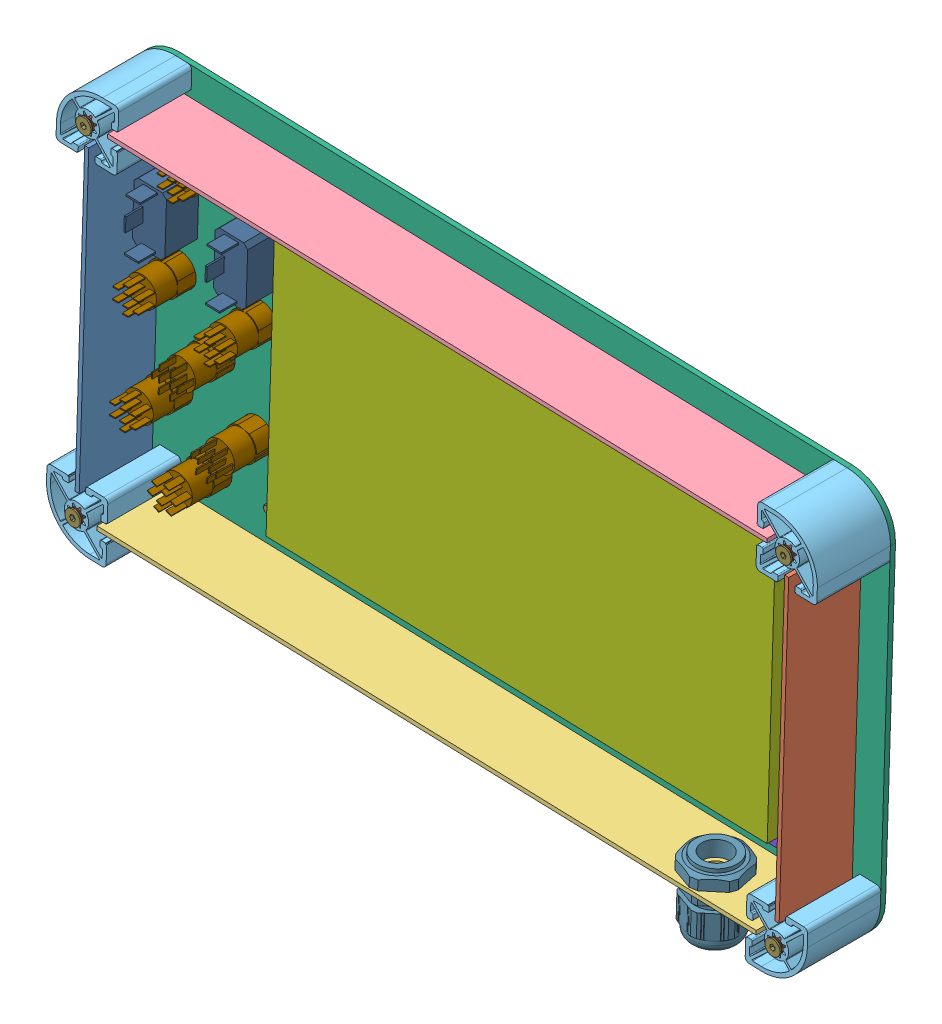
SolidWorks assembly BTEC 2019 - Montagem teclado, configuration Valor predeterminado. Lengths in mm.
Overall size (381.11 222.57 65).
42 component instances, 15 part files, 97 mates.
Components (placement in the parent):
- BTEC 2019 - Teclado base-1: BTEC 2019 - Teclado base [Default] at (-6.1201 -200.4879 117.0502) x (0.999504 -0.031491 0) z (0 0 1) size (375 200 2) (hidden)
- BTEC 2019 - Teclado lateral direita-1: BTEC 2019 - Teclado lateral direita [Valor predeterminado] at (-177.535 -195.0872 99.0502) x (-0.031491 -0.999504 0) z (0 0 1) size (150 2 36)
- BTEC 2019 - Teclado lateral esquerda-1: BTEC 2019 - Teclado lateral esquerda [Valor predeterminado] at (167.2938 -205.9515 99.0502) x (0.031491 0.999504 0) z (0 0 -1) size (150 2 36)
- BTEC 2019 - Teclado lateral inferior-1: BTEC 2019 - Teclado lateral inferior [Valor predeterminado] at (-8.7653 -284.4462 99.0502) x (0.999504 -0.031491 0) z (0 0 1) size (325 2 36)
- BTEC 2019 - Teclado lateral superior-1: BTEC 2019 - Teclado lateral superior [Valor predeterminado] at (-3.4749 -116.5295 99.0502) x (0.999504 -0.031491 0) z (0 0 -1) size (325 2 36)
- Perfil Famak 01 007 0027-1: Perfil Famak 01 007 0027 [Valor predeterminado] at (163.6176 -290.8779 181.0502) x (0 0 -1) z (0.031491 0.999504 0) size (36 30 30)
- Perfil Famak 01 007 0027-2: Perfil Famak 01 007 0027 [Valor predeterminado] at (168.9711 -120.9622 181.0502) x (0 0 -1) z (-0.999504 0.031491 0) size (36 30 30)
- Perfil Famak 01 007 0027-3: Perfil Famak 01 007 0027 [Valor predeterminado] at (-181.2113 -280.0135 181.0502) x (0 0 -1) z (0.999504 -0.031491 0) size (36 30 30)
- Perfil Famak 01 007 0027-4: Perfil Famak 01 007 0027 [Valor predeterminado] at (-175.8578 -110.0978 181.0502) x (0 0 -1) z (-0.031491 -0.999504 0) size (36 30 30)
- BTEC 2019 - Teclado moldura-1: BTEC 2019 - Teclado moldura [Default] at (-6.1201 -200.4879 79.8002) x (0.999504 -0.031491 0) z (0 0 -1) size (375 200 2.5)
- Placa eletronica-1: Placa eletronica [Valor predeterminado] at (72.0302 -209.9598 82.5502) x (0.999504 -0.031491 0) z (0 0 1) size (247 130 23)
- BTEC 2019 - Display 2-2: BTEC 2019 - Display 2 [Valor predeterminado] at (168.906 -315.4182 82.5502) x (-0.999504 0.031491 0) z (0 0 -1) size (279.5 158 1.5)
- BCV3 112 102 - Controle botão-1: BCV3 112 102 - Controle botão [Valor predeterminado] at (-126.2454 -186.6982 78.5502) x (1 0 0) z (0 1 0) size (17.7 39.7 17.7)
- BCV3 112 102 - Controle botão-2: BCV3 112 102 - Controle botão [Valor predeterminado] at (-127.82 -236.6734 78.5502) x (0.18993 0.981798 0) z (-0.981798 0.18993 0) size (17.7 39.7 17.7)
- BCV3 112 102 - Controle botão-3: BCV3 112 102 - Controle botão [Valor predeterminado] at (-148.5973 -261.0312 78.5502) x (0.921441 -0.388519 0) z (0.388519 0.921441 0) size (17.7 39.7 17.7)
- BCV3 112 102 - Controle botão-4: BCV3 112 102 - Controle botão [Valor predeterminado] at (-147.0228 -211.056 78.5502) x (0.025682 0.99967 0) z (-0.99967 0.025682 0) size (17.7 39.7 17.7)
- BCV3 112 102 - Controle botão-5: BCV3 112 102 - Controle botão [Valor predeterminado] at (-167.8001 -235.4137 78.5502) x (1 0 0) z (0 1 0) size (17.7 39.7 17.7)
- BCV3 112 102 - Controle botão-6: BCV3 112 102 - Controle botão [Valor predeterminado] at (-166.2256 -185.4385 78.5502) x (-0.999689 0.024955 0) z (-0.024955 -0.999689 0) size (17.7 39.7 17.7)
- BCV3 112 103 - Controle chave geral-1: BCV3 112 103 - Controle chave geral [Default] at (-165.2809 -155.4534 89.0502) x (-0.999504 0.031491 0) z (0 0 -1) size (17 29 51.5)
- BCV3 112 103 - Controle chave geral-2: BCV3 112 103 - Controle chave geral [Default] at (-125.3007 -156.713 89.0502) x (-0.999504 0.031491 0) z (0 0 -1) size (17 29 51.5)
- BCV3 112 102 - Controle botão-7: BCV3 112 102 - Controle botão [Valor predeterminado] at (-144.3461 -126.0981 78.5502) x (1 0 0) z (0 1 0) size (17.7 39.7 17.7)
- BTEC 2019 - Bucha M4-1: BTEC 2019 - Bucha M4 [Valor predeterminado] at (168.9711 -120.9622 99.0502) x (1 0 0) z (0 -1 0) size (6.5 36 6.5)
- BTEC 2019 - Bucha M4-2: BTEC 2019 - Bucha M4 [Valor predeterminado] at (163.6176 -290.8779 99.0502) x (1 0 0) z (0 -1 0) size (6.5 36 6.5)
- BTEC 2019 - Bucha M4-3: BTEC 2019 - Bucha M4 [Valor predeterminado] at (-175.8578 -110.0978 99.0502) x (1 0 0) z (0 -1 0) size (6.5 36 6.5)
- BTEC 2019 - Bucha M4-4: BTEC 2019 - Bucha M4 [Valor predeterminado] at (-181.2113 -280.0135 99.0502) x (-0.180459 -0.983583 0) z (-0.983583 0.180459 0) size (6.5 36 6.5)
- socket countersunk head screw_iso-2: socket countersunk head screw_iso [ISO 10642 - M4 x 12 --- 12N] at (163.6176 -290.8779 78.5502) x (0 0 1) z (-0.759789 -0.650169 0) size (12 7.53 7.53)
- socket countersunk head screw_iso-3: socket countersunk head screw_iso [ISO 10642 - M4 x 12 --- 12N] at (163.6176 -290.8779 119.0502) x (0 0 -1) z (0.525931 -0.850527 0) size (12 7.53 7.53)
- socket countersunk head screw_iso-4: socket countersunk head screw_iso [ISO 10642 - M4 x 12 --- 12N] at (-181.2113 -280.0135 78.5502) x (0 0 1) z (-1 0 0) size (12 7.53 7.53)
- socket countersunk head screw_iso-5: socket countersunk head screw_iso [ISO 10642 - M4 x 12 --- 12N] at (-175.8578 -110.0978 78.5502) x (0 0 1) z (0.031778 0.999495 0) size (12 7.53 7.53)
- socket countersunk head screw_iso-6: socket countersunk head screw_iso [ISO 10642 - M4 x 12 --- 12N] at (168.9711 -120.9622 78.5502) x (0 0 1) z (-1 0 0) size (12 7.53 7.53)
- socket countersunk head screw_iso-7: socket countersunk head screw_iso [ISO 10642 - M4 x 12 --- 12N] at (-181.2113 -280.0135 119.0502) x (0 0 -1) z (0.838265 0.545264 0) size (12 7.53 7.53)
- socket countersunk head screw_iso-8: socket countersunk head screw_iso [ISO 10642 - M4 x 12 --- 12N] at (-175.8578 -110.0978 119.0502) x (0 0 -1) z (0.635819 -0.771838 0) size (12 7.53 7.53)
- socket countersunk head screw_iso-9: socket countersunk head screw_iso [ISO 10642 - M4 x 12 --- 12N] at (168.9711 -120.9622 119.0502) x (0 0 -1) z (-0.751426 -0.659818 0) size (12 7.53 7.53)
- socket countersunk head screw_iso-10: socket countersunk head screw_iso [ISO 10642 - M4 x 12 --- 12N] at (156.9086 -265.6539 78.5502) x (0 0 1) z (-0.921096 -0.389335 0) size (12 7.53 7.53)
- socket countersunk head screw_iso-11: socket countersunk head screw_iso [ISO 10642 - M4 x 12 --- 12N] at (160.6875 -145.7134 78.5502) x (0 0 1) z (-0.921447 -0.388505 0) size (12 7.53 7.53)
- socket countersunk head screw_iso-12: socket countersunk head screw_iso [ISO 10642 - M4 x 12 --- 12N] at (-113.957 -257.1201 78.5502) x (0 0 1) z (-1 0 0) size (12 7.53 7.53)
- socket countersunk head screw_iso-13: socket countersunk head screw_iso [ISO 10642 - M4 x 12 --- 12N] at (-110.1781 -137.1796 78.5502) x (0 0 1) z (-1 0 0) size (12 7.53 7.53)
- hex nut style 1 gradeab_iso-1: hex nut style 1 gradeab_iso [Hexagon Nut ISO - 4032 - M4 - D - N] at (156.9086 -265.6539 85.7502) x (0.537158 -0.843482 0) z (0 0 1) size (7 8.08 3.2)
- hex nut style 1 gradeab_iso-2: hex nut style 1 gradeab_iso [Hexagon Nut ISO - 4032 - M4 - D - N] at (160.6875 -145.7134 85.7502) x (0.928496 0.371343 0) z (0 0 1) size (7 8.08 3.2)
- hex nut style 1 gradeab_iso-3: hex nut style 1 gradeab_iso [Hexagon Nut ISO - 4032 - M4 - D - N] at (-113.957 -257.1201 82.5502) x (0.678434 -0.734661 0) z (0 0 -1) size (7 8.08 3.2)
- hex nut style 1 gradeab_iso-4: hex nut style 1 gradeab_iso [Hexagon Nut ISO - 4032 - M4 - D - N] at (-110.1781 -137.1796 85.7502) size (7 8.08 3.2)
- PRENSA CABO STECK PG 13,5 S802 LI-2: PRENSA CABO STECK PG 13,5 S802 LI [Valor predeterminado] at (118.3502 -298.6562 102.0502) x (-0.031491 -0.999504 0) z (-0.315456 0.009939 0.948888) size (36 28.2 26.2)
Mates (geometry in assembly coordinates):
- Concêntrico46: concentric aligned: circle of BTEC 2019 - Teclado base-1; circle of Perfil Famak 01 007 0027-3
- Concêntrico47: concentric aligned: circle of BTEC 2019 - Teclado base-1; circle of Perfil Famak 01 007 0027-1
- Concêntrico48: concentric aligned: circle of BTEC 2019 - Teclado base-1; circle of Perfil Famak 01 007 0027-2
- Concêntrico49: concentric aligned: circle of BTEC 2019 - Teclado base-1; circle of Perfil Famak 01 007 0027-4
- Coincidente29: coincident anti-aligned: plane of BTEC 2019 - Teclado base-1 through (156.8415 -283.6609 117.0502) normal (0 0 -1); plane of Perfil Famak 01 007 0027-2 through (7.7937 -130.8915 117.0502) normal (0 0 1)
- Coincidente31: coincident anti-aligned: plane of BTEC 2019 - Teclado base-1 through (156.8415 -283.6609 117.0502) normal (0 0 -1); plane of Perfil Famak 01 007 0027-1 through (153.6883 -129.7005 117.0502) normal (0 0 1)
- Coincidente32: coincident anti-aligned: plane of BTEC 2019 - Teclado base-1 through (156.8415 -283.6609 117.0502) normal (0 0 -1); plane of Perfil Famak 01 007 0027-3 through (-20.0339 -270.0842 117.0502) normal (0 0 1)
- Coincidente33: coincident anti-aligned: plane of BTEC 2019 - Teclado base-1 through (156.8415 -283.6609 117.0502) normal (0 0 -1); plane of Perfil Famak 01 007 0027-4 through (-165.9285 -271.2752 117.0502) normal (0 0 1)
- Paralelo1: parallel anti-aligned: plane of BTEC 2019 - Teclado base-1 through (-174.6871 -295.2265 119.0502) normal (-0.031491 -0.999504 0); plane of Perfil Famak 01 007 0027-1 through (159.4923 -275.7404 81.0502) normal (0.031491 0.999504 0)
- Paralelo2: parallel anti-aligned: plane of BTEC 2019 - Teclado base-1 through (183.7432 -128.4311 119.0502) normal (0.999504 -0.031491 0); plane of Perfil Famak 01 007 0027-2 through (153.8336 -125.0875 81.0502) normal (-0.999504 0.031491 0)
- Paralelo3: parallel anti-aligned: plane of BTEC 2019 - Teclado base-1 through (-174.6871 -295.2265 119.0502) normal (-0.031491 -0.999504 0); plane of Perfil Famak 01 007 0027-3 through (-185.3366 -264.8761 81.0502) normal (0.031491 0.999504 0)
- Paralelo4: parallel anti-aligned: plane of BTEC 2019 - Teclado base-1 through (-168.3889 -95.3257 119.0502) normal (0.031491 0.999504 0); plane of Perfil Famak 01 007 0027-4 through (-171.7325 -125.2353 81.0502) normal (-0.031491 -0.999504 0)
- Coincidente42: coincident anti-aligned: plane of BTEC 2019 - Teclado base-1 through (156.8415 -283.6609 117.0502) normal (0 0 -1); plane of BTEC 2019 - Teclado lateral direita-1 through (-181.8959 -269.987 117.0502) normal (0 0 1)
- Distância1: distance = 5 mm anti-aligned: plane of BTEC 2019 - Teclado lateral direita-1 through (-177.1722 -120.0614 81.0502) normal (0.031491 0.999504 0); plane of Perfil Famak 01 007 0027-4 through (-189.3237 -124.681 81.0502) normal (-0.031491 -0.999504 0)
- Distância2: distance = 3.1 mm anti-aligned: plane of Perfil Famak 01 007 0027-4 through (-180.4124 -124.4615 81.0502) normal (0.999504 -0.031491 0); plane of BTEC 2019 - Teclado lateral direita-1 through (-181.8959 -269.987 117.0502) normal (-0.999504 0.031491 0)
- Coincidente46: coincident anti-aligned: plane of BTEC 2019 - Teclado base-1 through (156.8415 -283.6609 117.0502) normal (0 0 -1); plane of BTEC 2019 - Teclado lateral esquerda-1 through (169.6557 -130.9887 117.0502) normal (0 0 1)
- Distância4: distance = 5 mm anti-aligned: plane of BTEC 2019 - Teclado lateral esquerda-1 through (167.6567 -130.9257 117.0502) normal (0.031491 0.999504 0); plane of Perfil Famak 01 007 0027-2 through (173.0964 -136.0996 81.0502) normal (-0.031491 -0.999504 0)
- Coincidente49: coincident anti-aligned: plane of BTEC 2019 - Teclado base-1 through (156.8415 -283.6609 117.0502) normal (0 0 -1); plane of BTEC 2019 - Teclado lateral superior-1 through (158.9445 -121.6468 117.0502) normal (0 0 1)
- Distância5: distance = 5 mm anti-aligned: plane of BTEC 2019 - Teclado lateral superior-1 through (-165.8313 -109.4133 117.0502) normal (-0.999504 0.031491 0); plane of Perfil Famak 01 007 0027-4 through (-161.2747 -123.5638 81.0502) normal (0.999504 -0.031491 0)
- Distância6: distance = 3.1 mm anti-aligned: plane of BTEC 2019 - Teclado lateral superior-1 through (159.0075 -119.6478 81.0502) normal (0.031491 0.999504 0); plane of Perfil Famak 01 007 0027-4 through (-163.3863 -106.3887 81.0502) normal (-0.031491 -0.999504 0)
- Coincidente52: coincident anti-aligned: plane of BTEC 2019 - Teclado base-1 through (156.8415 -283.6609 117.0502) normal (0 0 -1); plane of BTEC 2019 - Teclado lateral inferior-1 through (153.5911 -291.5625 117.0502) normal (0 0 1)
- Coincidente72: coincident anti-aligned: plane of Perfil Famak 01 007 0027-1 through (151.0335 -277.4749 81.0502) normal (0 0 -1); plane of BTEC 2019 - Teclado moldura-1 through (161.7541 -127.7383 81.0502) normal (0 0 1)
- Distância11: distance = 3.1 mm anti-aligned: plane of Perfil Famak 01 007 0027-1 through (168.1722 -276.5142 81.0502) normal (-0.999504 0.031491 0); plane of BTEC 2019 - Teclado lateral esquerda-1 through (169.6557 -130.9887 81.0502) normal (0.999504 -0.031491 0)
- Distância21: distance = 16 mm anti-aligned: plane of Placa eletronica-1 through (147.5393 -261.3569 105.5502) normal (0.999504 -0.031491 0); plane of BTEC 2019 - Teclado lateral esquerda-1 through (167.6567 -130.9257 81.0502) normal (-0.999504 0.031491 0)
- Concêntrico54: concentric anti-aligned: circle of Perfil Famak 01 007 0027-4; circle of BTEC 2019 - Teclado moldura-1
- Concêntrico55: concentric anti-aligned: circle of Perfil Famak 01 007 0027-2; circle of BTEC 2019 - Teclado moldura-1
- Concêntrico56: concentric anti-aligned: circle of Perfil Famak 01 007 0027-1; circle of BTEC 2019 - Teclado moldura-1
- Concêntrico57: concentric anti-aligned: circle of Perfil Famak 01 007 0027-3; circle of BTEC 2019 - Teclado moldura-1
- Coincidente91: coincident anti-aligned: plane of BTEC 2019 - Teclado moldura-1 through (161.7541 -127.7383 81.0502) normal (0 0 1); plane of BTEC 2019 - Display 2-2 through (168.906 -315.4182 81.0502) normal (0 0 -1)
- Distância23: distance = 1.5 mm anti-aligned: plane of BTEC 2019 - Display 2-2 through (165.9684 -136.8755 72.5502) normal (0.999504 -0.031491 0); plane of BTEC 2019 - Teclado lateral esquerda-1 through (167.6567 -130.9257 81.0502) normal (-0.999504 0.031491 0)
- Distância24: distance = 5 mm aligned: plane of Placa eletronica-1 through (-95.2444 -123.6431 105.5502) normal (0.031491 0.999504 0); plane of BTEC 2019 - Display 2-2 through (174.8377 -127.15 81.0502) normal (0.031491 0.999504 0)
- Concêntrico58: concentric aligned: cylinder of BTEC 2019 - Teclado moldura-1 through (-126.2454 -186.6982 88.5502) axis (0 0 -1) radius 8; cylinder of BCV3 112 102 - Controle botão-1 through (-126.2454 -186.6982 99.8502) axis (0 0 -1) radius 7.25
- Coincidente92: coincident anti-aligned: plane of BTEC 2019 - Teclado moldura-1 through (161.7541 -127.7383 78.5502) normal (0 0 -1); plane of BCV3 112 102 - Controle botão-1 through (-126.2454 -186.6982 78.5502) normal (0 0 1)
- Concêntrico59: concentric anti-aligned: cylinder of BTEC 2019 - Teclado moldura-1 through (-166.2256 -185.4385 88.5502) axis (0 0 -1) radius 8; cylinder of BCV3 112 102 - Controle botão-6 through (-166.2256 -185.4385 72.1502) axis (0 0 1) radius 8.85
- Coincidente93: coincident anti-aligned: plane of BTEC 2019 - Teclado moldura-1 through (161.7541 -127.7383 78.5502) normal (0 0 -1); plane of BCV3 112 102 - Controle botão-6 through (-166.2256 -185.4385 78.5502) normal (0 0 1)
- Concêntrico60: concentric anti-aligned: circle of BTEC 2019 - Teclado moldura-1; cylinder of BCV3 112 102 - Controle botão-4 through (-147.0228 -211.056 99.8502) axis (0 0 -1) radius 7.25
- Coincidente95: coincident anti-aligned: plane of BTEC 2019 - Teclado moldura-1 through (161.7541 -127.7383 78.5502) normal (0 0 -1); plane of BCV3 112 102 - Controle botão-4 through (-147.0228 -211.056 78.5502) normal (0 0 1)
- Coincidente96: coincident anti-aligned: plane of BTEC 2019 - Teclado moldura-1 through (161.7541 -127.7383 78.5502) normal (0 0 -1); plane of BCV3 112 102 - Controle botão-2 through (-127.82 -236.6734 78.5502) normal (0 0 1)
- Coincidente97: coincident anti-aligned: plane of BTEC 2019 - Teclado moldura-1 through (161.7541 -127.7383 78.5502) normal (0 0 -1); plane of BCV3 112 102 - Controle botão-3 through (-148.5973 -261.0312 78.5502) normal (0 0 1)
- Coincidente98: coincident anti-aligned: plane of BTEC 2019 - Teclado moldura-1 through (161.7541 -127.7383 78.5502) normal (0 0 -1); plane of BCV3 112 102 - Controle botão-5 through (-167.8001 -235.4137 78.5502) normal (0 0 1)
- Concêntrico61: concentric aligned: cylinder of BTEC 2019 - Teclado moldura-1 through (-167.8001 -235.4137 88.5502) axis (0 0 -1) radius 8; cylinder of BCV3 112 102 - Controle botão-5 through (-167.8001 -235.4137 99.8502) axis (0 0 -1) radius 7.25
- Concêntrico62: concentric anti-aligned: circle of BTEC 2019 - Teclado moldura-1; cylinder of BCV3 112 102 - Controle botão-3 through (-148.5973 -261.0312 99.8502) axis (0 0 -1) radius 7.25
- Concêntrico63: concentric aligned: cylinder of BTEC 2019 - Teclado moldura-1 through (-127.82 -236.6734 88.5502) axis (0 0 -1) radius 8; cylinder of BCV3 112 102 - Controle botão-2 through (-127.82 -236.6734 99.8502) axis (0 0 -1) radius 7.25
- Concêntrico65: concentric anti-aligned: cylinder of BTEC 2019 - Teclado moldura-1 through (-165.2809 -155.4534 88.5502) axis (0 0 -1) radius 6; cylinder of BCV3 112 103 - Controle chave geral-1 through (-165.2809 -155.4534 68.0502) axis (0 0 1) radius 5.85
- Coincidente100: coincident anti-aligned: plane of BTEC 2019 - Teclado moldura-1 through (161.7541 -127.7383 81.0502) normal (0 0 1); plane of BCV3 112 103 - Controle chave geral-1 through (-157.7415 -170.1982 81.0502) normal (0 0 -1)
- Paralelo5: parallel aligned: plane of BTEC 2019 - Teclado moldura-1 through (-195.9834 -272.5446 78.5502) normal (-0.999504 0.031491 0); plane of BCV3 112 103 - Controle chave geral-1 through (-172.8203 -140.7087 81.0502) normal (-0.999504 0.031491 0)
- Concêntrico66: concentric anti-aligned: cylinder of BTEC 2019 - Teclado moldura-1 through (-125.3007 -156.713 88.5502) axis (0 0 -1) radius 6; cylinder of BCV3 112 103 - Controle chave geral-2 through (-125.3007 -156.713 68.0502) axis (0 0 1) radius 5.85
- Coincidente102: coincident anti-aligned: plane of BTEC 2019 - Teclado moldura-1 through (161.7541 -127.7383 81.0502) normal (0 0 1); plane of BCV3 112 103 - Controle chave geral-2 through (-117.7613 -171.4578 81.0502) normal (0 0 -1)
- Paralelo6: parallel aligned: plane of BTEC 2019 - Teclado lateral direita-1 through (-181.8959 -269.987 117.0502) normal (-0.999504 0.031491 0); plane of BCV3 112 103 - Controle chave geral-2 through (-132.8401 -141.9683 81.0502) normal (-0.999504 0.031491 0)
- Concêntrico67: concentric aligned: cylinder of BTEC 2019 - Teclado moldura-1 through (-144.3461 -126.0981 88.5502) axis (0 0 -1) radius 8; cylinder of BCV3 112 102 - Controle botão-7 through (-144.3461 -126.0981 99.8502) axis (0 0 -1) radius 7.25
- Coincidente104: coincident anti-aligned: plane of BTEC 2019 - Teclado moldura-1 through (161.7541 -127.7383 78.5502) normal (0 0 -1); plane of BCV3 112 102 - Controle botão-7 through (-144.3461 -126.0981 78.5502) normal (0 0 1)
- Coincidente105: coincident anti-aligned: plane of Placa eletronica-1 through (72.0302 -209.9598 82.5502) normal (0 0 -1); plane of BTEC 2019 - Display 2-2 through (168.906 -315.4182 82.5502) normal (0 0 1)
- Distância25: distance = 1 mm anti-aligned: plane of Perfil Famak 01 007 0027-2 through (155.5051 -135.5454 81.0502) normal (-0.031491 -0.999504 0); plane of BTEC 2019 - Display 2-2 through (174.5228 -137.145 81.0502) normal (0.031491 0.999504 0)
- Concêntrico68: concentric anti-aligned: cylinder of Perfil Famak 01 007 0027-4 through (-175.8578 -110.0978 81.0502) axis (0 0 1) radius 3.25; cylinder of BTEC 2019 - Bucha M4-3 through (-175.8578 -110.0978 117.0502) axis (0 0 -1) radius 3.25
- Coincidente106: coincident anti-aligned: plane of BTEC 2019 - Teclado moldura-1 through (161.7541 -127.7383 81.0502) normal (0 0 1); plane of BTEC 2019 - Bucha M4-3 through (-175.8578 -110.0978 81.0502) normal (0 0 -1)
- Concêntrico69: concentric anti-aligned: cylinder of Perfil Famak 01 007 0027-3 through (-181.2113 -280.0135 81.0502) axis (0 0 1) radius 3.25; cylinder of BTEC 2019 - Bucha M4-4 through (-181.2113 -280.0135 117.0502) axis (0 0 -1) radius 3.25
- Coincidente107: coincident anti-aligned: plane of BTEC 2019 - Teclado moldura-1 through (161.7541 -127.7383 81.0502) normal (0 0 1); plane of BTEC 2019 - Bucha M4-4 through (-181.2113 -280.0135 81.0502) normal (0 0 -1)
- Concêntrico70: concentric anti-aligned: cylinder of Perfil Famak 01 007 0027-2 through (168.9711 -120.9622 81.0502) axis (0 0 1) radius 3.25; cylinder of BTEC 2019 - Bucha M4-1 through (168.9711 -120.9622 117.0502) axis (0 0 -1) radius 3.25
- Coincidente108: coincident anti-aligned: plane of BTEC 2019 - Teclado moldura-1 through (161.7541 -127.7383 81.0502) normal (0 0 1); plane of BTEC 2019 - Bucha M4-1 through (168.9711 -120.9622 81.0502) normal (0 0 -1)
- Concêntrico71: concentric anti-aligned: cylinder of Perfil Famak 01 007 0027-1 through (163.6176 -290.8779 81.0502) axis (0 0 1) radius 3.25; cylinder of BTEC 2019 - Bucha M4-2 through (163.6176 -290.8779 117.0502) axis (0 0 -1) radius 3.25
- Coincidente110: coincident anti-aligned: plane of BTEC 2019 - Teclado moldura-1 through (161.7541 -127.7383 81.0502) normal (0 0 1); plane of BTEC 2019 - Bucha M4-2 through (163.6176 -290.8779 81.0502) normal (0 0 -1)
- Concêntrico72: concentric anti-aligned: cylinder of BTEC 2019 - Bucha M4-2 through (163.6176 -290.8779 117.0502) axis (0 0 1) radius 1.65; cylinder of socket countersunk head screw_iso-2 through (163.6176 -290.8779 78.5502) axis (0 0 -1) radius 2
- Coincidente111: coincident aligned: plane of BTEC 2019 - Teclado moldura-1 through (161.7541 -127.7383 78.5502) normal (0 0 -1); plane of socket countersunk head screw_iso-2 through (163.6176 -290.8779 78.5502) normal (0 0 -1)
- Concêntrico73: concentric aligned: cylinder of BTEC 2019 - Bucha M4-2 through (163.6176 -290.8779 117.0502) axis (0 0 1) radius 1.65; cylinder of socket countersunk head screw_iso-3 through (163.6176 -290.8779 119.0502) axis (0 0 1) radius 2
- Coincidente112: coincident aligned: plane of BTEC 2019 - Teclado base-1 through (156.8415 -283.6609 119.0502) normal (0 0 1); plane of socket countersunk head screw_iso-3 through (163.6176 -290.8779 119.0502) normal (0 0 1)
- Concêntrico74: concentric anti-aligned: cylinder of BTEC 2019 - Bucha M4-3 through (-175.8578 -110.0978 117.0502) axis (0 0 1) radius 1.65; cylinder of socket countersunk head screw_iso-5 through (-175.8578 -110.0978 78.5502) axis (0 0 -1) radius 2
- Coincidente113: coincident aligned: plane of BTEC 2019 - Teclado moldura-1 through (161.7541 -127.7383 78.5502) normal (0 0 -1); plane of socket countersunk head screw_iso-5 through (-175.8578 -110.0978 78.5502) normal (0 0 -1)
- Concêntrico75: concentric anti-aligned: cylinder of BTEC 2019 - Bucha M4-4 through (-181.2113 -280.0135 117.0502) axis (0 0 1) radius 1.65; cylinder of socket countersunk head screw_iso-4 through (-181.2113 -280.0135 78.5502) axis (0 0 -1) radius 2
- Coincidente114: coincident aligned: plane of BTEC 2019 - Teclado moldura-1 through (161.7541 -127.7383 78.5502) normal (0 0 -1); circle of socket countersunk head screw_iso-4
- Concêntrico76: concentric anti-aligned: cylinder of BTEC 2019 - Bucha M4-1 through (168.9711 -120.9622 117.0502) axis (0 0 1) radius 1.65; cylinder of socket countersunk head screw_iso-6 through (168.9711 -120.9622 78.5502) axis (0 0 -1) radius 2
- Coincidente115: coincident aligned: plane of BTEC 2019 - Teclado moldura-1 through (161.7541 -127.7383 78.5502) normal (0 0 -1); plane of socket countersunk head screw_iso-6 through (168.9711 -120.9622 78.5502) normal (0 0 -1)
- Concêntrico77: concentric aligned: cylinder of BTEC 2019 - Bucha M4-1 through (168.9711 -120.9622 117.0502) axis (0 0 1) radius 1.65; cylinder of socket countersunk head screw_iso-9 through (168.9711 -120.9622 119.0502) axis (0 0 1) radius 2
- Coincidente116: coincident aligned: plane of BTEC 2019 - Teclado base-1 through (156.8415 -283.6609 119.0502) normal (0 0 1); plane of socket countersunk head screw_iso-9 through (168.9711 -120.9622 119.0502) normal (0 0 1)
- Concêntrico78: concentric aligned: cylinder of BTEC 2019 - Bucha M4-3 through (-175.8578 -110.0978 117.0502) axis (0 0 1) radius 1.65; cylinder of socket countersunk head screw_iso-8 through (-175.8578 -110.0978 119.0502) axis (0 0 1) radius 2
- Coincidente118: coincident aligned: plane of BTEC 2019 - Teclado base-1 through (156.8415 -283.6609 119.0502) normal (0 0 1); plane of socket countersunk head screw_iso-8 through (-175.8578 -110.0978 119.0502) normal (0 0 1)
- Concêntrico79: concentric aligned: cylinder of BTEC 2019 - Bucha M4-4 through (-181.2113 -280.0135 117.0502) axis (0 0 1) radius 1.65; cylinder of socket countersunk head screw_iso-7 through (-181.2113 -280.0135 119.0502) axis (0 0 1) radius 2
- Coincidente119: coincident aligned: plane of BTEC 2019 - Teclado base-1 through (156.8415 -283.6609 119.0502) normal (0 0 1); plane of socket countersunk head screw_iso-7 through (-181.2113 -280.0135 119.0502) normal (0 0 1)
- Concêntrico80: concentric aligned: cylinder of BTEC 2019 - Display 2-2 through (160.6875 -145.7134 82.5503) axis (0 0 -1) radius 2; cylinder of socket countersunk head screw_iso-11 through (160.6875 -145.7134 78.5502) axis (0 0 -1) radius 2
- Coincidente120: coincident aligned: plane of BTEC 2019 - Teclado moldura-1 through (161.7541 -127.7383 78.5502) normal (0 0 -1); plane of socket countersunk head screw_iso-11 through (160.6875 -145.7134 78.5502) normal (0 0 -1)
- Concêntrico81: concentric aligned: cylinder of BTEC 2019 - Display 2-2 through (156.9086 -265.6539 82.5503) axis (0 0 -1) radius 2; cylinder of socket countersunk head screw_iso-10 through (156.9086 -265.6539 78.5502) axis (0 0 -1) radius 2
- Coincidente121: coincident aligned: plane of BTEC 2019 - Teclado moldura-1 through (161.7541 -127.7383 78.5502) normal (0 0 -1); plane of socket countersunk head screw_iso-10 through (156.9086 -265.6539 78.5502) normal (0 0 -1)
- Concêntrico82: concentric aligned: cylinder of BTEC 2019 - Display 2-2 through (-113.957 -257.1201 82.5503) axis (0 0 -1) radius 2; cylinder of socket countersunk head screw_iso-12 through (-113.957 -257.1201 78.5502) axis (0 0 -1) radius 2
- Coincidente122: coincident aligned: plane of BTEC 2019 - Teclado moldura-1 through (161.7541 -127.7383 78.5502) normal (0 0 -1); plane of socket countersunk head screw_iso-12 through (-113.957 -257.1201 78.5502) normal (0 0 -1)
- Concêntrico83: concentric aligned: cylinder of BTEC 2019 - Display 2-2 through (-110.1781 -137.1796 82.5503) axis (0 0 -1) radius 2; cylinder of socket countersunk head screw_iso-13 through (-110.1781 -137.1796 78.5502) axis (0 0 -1) radius 2
- Coincidente123: coincident aligned: plane of BTEC 2019 - Teclado moldura-1 through (161.7541 -127.7383 78.5502) normal (0 0 -1); plane of socket countersunk head screw_iso-13 through (-110.1781 -137.1796 78.5502) normal (0 0 -1)
- Concêntrico84: concentric aligned: cone of socket countersunk head screw_iso-10 through (156.9086 -265.6539 90.5502) axis (0 0 1); cylinder of hex nut style 1 gradeab_iso-1 through (156.9086 -265.6539 60.7127) axis (0 0 1) radius 2
- Concêntrico85: concentric aligned: cone of socket countersunk head screw_iso-11 through (160.6875 -145.7134 90.5502) axis (0 0 1); cylinder of hex nut style 1 gradeab_iso-2 through (160.6875 -145.7134 60.7127) axis (0 0 1) radius 2
- Concêntrico86: concentric aligned: cylinder of socket countersunk head screw_iso-12 through (-113.957 -257.1201 78.5502) axis (0 0 -1) radius 2; cylinder of hex nut style 1 gradeab_iso-3 through (-113.957 -257.1201 107.5877) axis (0 0 -1) radius 2
- Coincidente130: coincident anti-aligned: plane of BTEC 2019 - Display 2-2 through (168.906 -315.4182 82.5502) normal (0 0 1); plane of hex nut style 1 gradeab_iso-2 through (159.1868 -141.961 82.5502) normal (0 0 -1)
- Coincidente131: coincident anti-aligned: plane of BTEC 2019 - Display 2-2 through (168.906 -315.4182 82.5502) normal (0 0 1); plane of hex nut style 1 gradeab_iso-1 through (160.3175 -263.483 82.5502) normal (0 0 -1)
- Coincidente132: coincident anti-aligned: plane of BTEC 2019 - Display 2-2 through (168.906 -315.4182 82.5502) normal (0 0 1); plane of hex nut style 1 gradeab_iso-3 through (-116.9261 -259.8619 82.5502) normal (0 0 -1)
- Coincidente133: coincident anti-aligned: plane of BTEC 2019 - Display 2-2 through (168.906 -315.4182 82.5502) normal (0 0 1); plane of hex nut style 1 gradeab_iso-4 through (-110.1781 -133.1381 82.5502) normal (0 0 -1)
- Concêntrico87: concentric anti-aligned: cylinder of socket countersunk head screw_iso-13 through (-110.1781 -137.1796 78.5502) axis (0 0 -1) radius 2; cylinder of hex nut style 1 gradeab_iso-4 through (-110.1781 -137.1796 82.5502) axis (0 0 1) radius 1.65
- Distância26: distance = 5 mm anti-aligned: plane of BTEC 2019 - Teclado lateral inferior-1 through (153.5911 -291.5625 81.0502) normal (0.999504 -0.031491 0); plane of Perfil Famak 01 007 0027-1 through (148.4802 -295.0032 81.0502) normal (-0.999504 0.031491 0)
- Distância28: distance = 3.1 mm anti-aligned: plane of BTEC 2019 - Teclado lateral inferior-1 through (153.5911 -291.5625 117.0502) normal (-0.031491 -0.999504 0); plane of Perfil Famak 01 007 0027-1 through (151.1461 -294.587 81.0502) normal (0.031491 0.999504 0)
- Concêntrico89: concentric anti-aligned: cylinder of BTEC 2019 - Teclado lateral inferior-1 through (118.6714 -288.4613 102.0502) axis (-0.031491 -0.999504 0) radius 5; cylinder of PRENSA CABO STECK PG 13,5 S802 LI-2 through (117.7834 -316.6473 102.0502) axis (0.031491 0.999504 0) radius 7
- Coincidente138: coincident anti-aligned: plane of BTEC 2019 - Teclado lateral inferior-1 through (153.6541 -289.5634 117.0502) normal (0.031491 0.999504 0); plane of PRENSA CABO STECK PG 13,5 S802 LI-2 through (118.6714 -288.4613 102.0502) normal (-0.031491 -0.999504 0)
